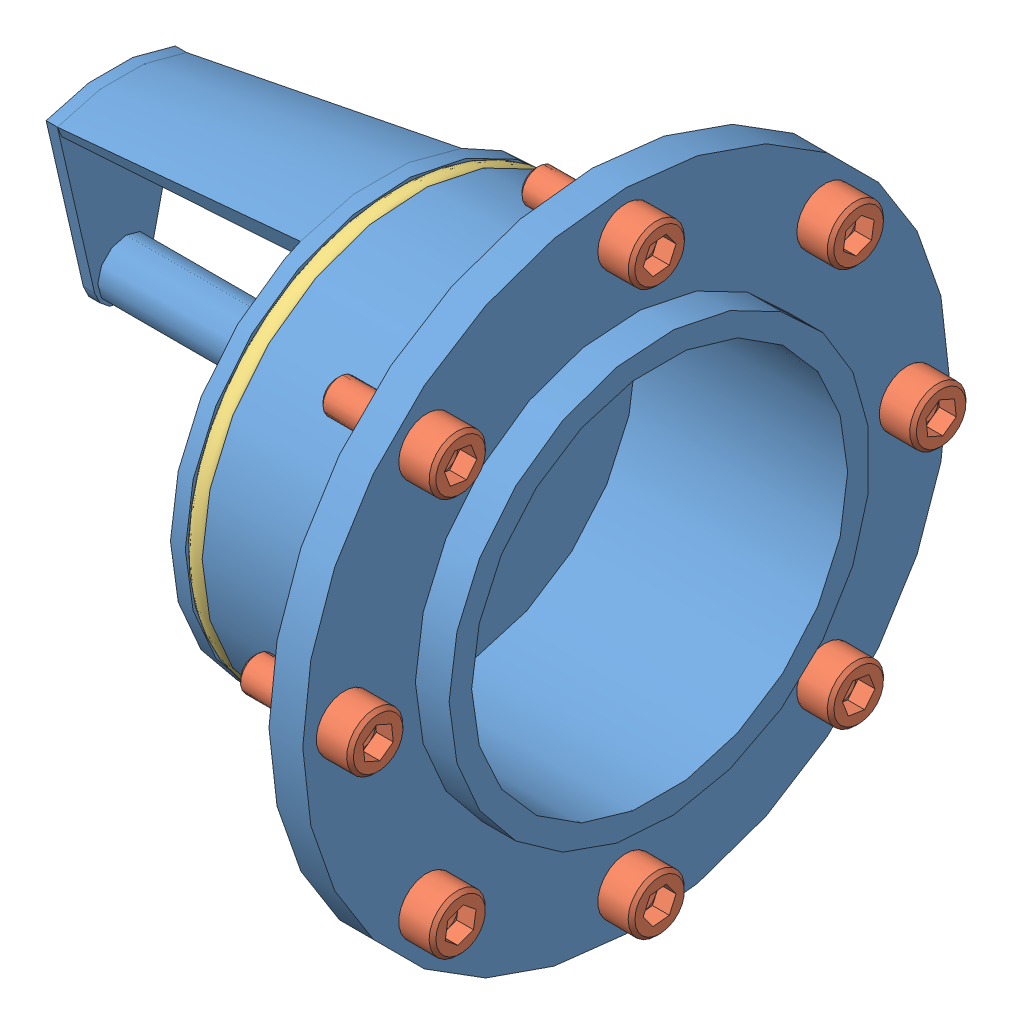
SolidWorks assembly rf_input_assy_a_1107, configuration Default. Lengths in mm.
Overall size (97.5 114.8 114.8).
11 component instances, 4 part files, 8 mates.
Components (placement in the parent):
- rf_input_fitting_a_1107-1: rf_input_fitting_a_1107 [Default] at origin size (97.5 114.8 114.8)
- Socket Head Cap Screw_AM-1: Socket Head Cap Screw_AM [B18.3.1M - 6 x 1.0 x 16 Hex SHCS -- 16NHX] at (49.5 35.3553 -35.3553) x (-1 0 0) z (0 -0.934069 -0.357093) size (22 10 10)
- Socket Head Cap Screw_AM-2: Socket Head Cap Screw_AM [B18.3.1M - 6 x 1.0 x 16 Hex SHCS -- 16NHX] at (49.5 0 -50) x (-1 0 0) z (0 -0.912989 0.407983) size (22 10 10)
- Socket Head Cap Screw_AM-3: Socket Head Cap Screw_AM [B18.3.1M - 6 x 1.0 x 16 Hex SHCS -- 16NHX] at (49.5 -35.3553 -35.3553) x (-1 0 0) z (0 -0.357093 0.934069) size (22 10 10)
- Socket Head Cap Screw_AM-4: Socket Head Cap Screw_AM [B18.3.1M - 6 x 1.0 x 16 Hex SHCS -- 16NHX] at (49.5 -50 0) x (-1 0 0) z (0 0.407983 0.912989) size (22 10 10)
- Socket Head Cap Screw_AM-5: Socket Head Cap Screw_AM [B18.3.1M - 6 x 1.0 x 16 Hex SHCS -- 16NHX] at (49.5 -35.3553 35.3553) x (-1 0 0) z (0 0.934069 0.357093) size (22 10 10)
- Socket Head Cap Screw_AM-6: Socket Head Cap Screw_AM [B18.3.1M - 6 x 1.0 x 16 Hex SHCS -- 16NHX] at (49.5 0 50) x (-1 0 0) z (0 0.912989 -0.407983) size (22 10 10)
- Socket Head Cap Screw_AM-7: Socket Head Cap Screw_AM [B18.3.1M - 6 x 1.0 x 16 Hex SHCS -- 16NHX] at (49.5 35.3553 35.3553) x (-1 0 0) z (0 0.357093 -0.934069) size (22 10 10)
- Socket Head Cap Screw_AM-8: Socket Head Cap Screw_AM [B18.3.1M - 6 x 1.0 x 16 Hex SHCS -- 16NHX] at (49.5 50 0) x (-1 0 0) z (0 -0.407983 -0.912989) size (22 10 10)
- rf_input_canted_1107-1: rf_input_canted_1107 [Default] at (4.1347 0 0) x (0 -1 0) z (0 0 1) size (74.8 3 74.8)
- rf_input_oring_1107-1: rf_input_oring_1107 [Default] at (38 0 0) x (0 1 0) z (0 0 1) size (85 1.5 85)
Mates (geometry in assembly coordinates):
- Coincident1: coincident anti-aligned: plane of rf_input_fitting_a_1107-1 through (43.5 57.4 0) normal (1 0 0); plane of Socket Head Cap Screw_AM-1 through (43.5 37.1408 -40.0257) normal (-1 0 0)
- Concentric1: concentric aligned: cylinder of rf_input_fitting_a_1107-1 through (43.5 35.3553 -35.3553) axis (1 0 0) radius 3.25; cylinder of Socket Head Cap Screw_AM-1 through (81.25 35.3553 -35.3553) axis (1 0 0) radius 3
- Coincident2: coincident aligned: plane of ? through (38.03 0 0) normal (0 0 1)
- Coincident3: coincident anti-aligned: unknown of ?
- Coincident4: coincident aligned: plane of rf_input_oring_1107-1; plane of assembly
- Coincident5: coincident aligned: plane of rf_input_oring_1107-1 through (38 0 0) normal (0 0 1)
- Tangent1: tangent: plane of rf_input_fitting_a_1107-1 through (38.75 40 0) normal (-1 0 0); face of rf_input_oring_1107-1
- Distance1: distance = 1.5 mm aligned: plane of rf_input_canted_1107-1; plane of rf_input_fitting_a_1107-1 through (2.6347 37.4 0) normal (1 0 0)
